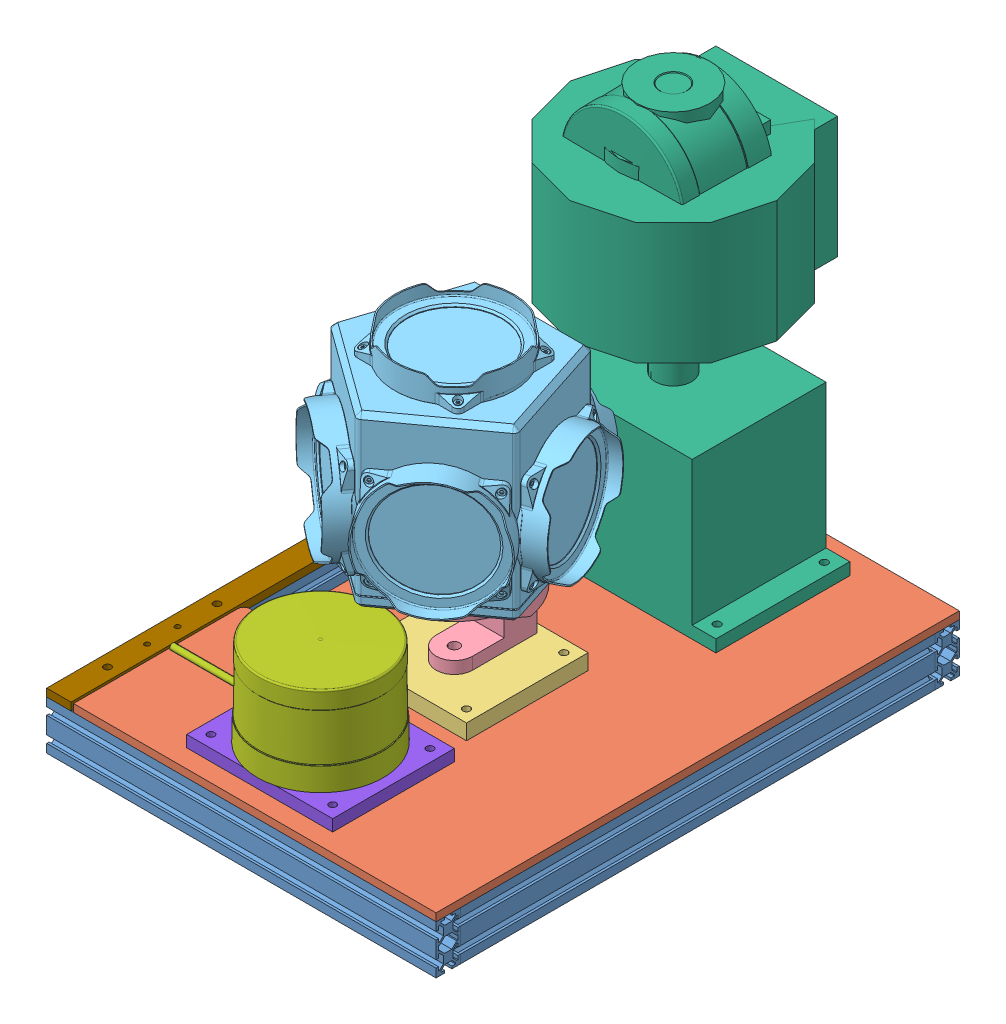
SolidWorks assembly complete_assembly, configuration Default. Lengths in mm.
Overall size (320 379.99 453.62).
14 component instances, 9 part files, 14 mates.
Components (placement in the parent):
- fence-1: fence [Default] at (0 -20 0) size (320 40 430)
  - 2040_extrusion-1: 2040_extrusion [320] at (0 20 205) x (0 0 1) z (-1 0 0) size (20 40 320)
  - 2040_extrusion-2: 2040_extrusion [390] at (150 20 0) size (20 40 390)
  - 2040_extrusion-3: 2040_extrusion [390] at (-150 20 0) x (-1 0 0) z (0 0 -1) size (20 40 390)
  - 2040_extrusion-4: 2040_extrusion [320] at (0 20 -205) x (0 0 -1) z (1 0 0) size (20 40 320)
- sensor_suite-1: sensor_suite [Default] at (0 20 0) size (298 339.99 453.62)
  - deck_lid-1: deck_lid [Default] at origin size (298 6.35 430)
  - Ladybug_mount_plate-1: Ladybug_mount_plate [Default] at (0 6.35 40) size (100 12.7 100)
  - OEM_Mount-1: OEM_Mount [Default] at (0 19.05 40) size (110 76.2 102.63)
  - LD5-001-R0-1: LD5-001-R0 [Default] at (0 155.75 40) x (-1 0 0) z (0 0 -1) size (192.91 159.78 183.75)
  - lidar_rotater-1: lidar_rotater [Default] at (0 6.35 -140) x (0 0 -1) z (1 0 0) size (197.23 333.64 197.23)
  - VLP-16-1: VLP-16 [Default] at (0 15.875 150) x (-1 0 0) z (0 0 -1) size (232.88 72.75 103.27)
  - Lidar_mount_plate-1: Lidar_mount_plate [Default] at (0 15.875 150) x (1 0 0) z (0 0 -1) size (120 9.53 100)
- Hinge_mount_plate-1: Hinge_mount_plate [Default] at (-150 20 0) x (-1 0 0) z (0 0 -1) size (20 6.35 430)
Mates (geometry in assembly coordinates):
- Coincident1: coincident aligned: plane of Fence-1 through (0 -20 0) normal (0 0 1); plane of assembly through (0 0 0) normal (0 0 1)
- Distance1: distance = 20 mm: plane of assembly through (0 0 0) normal (0 1 0); plane of Fence-1 through (0 -20 0) normal (0 1 0)
- Coincident3: coincident aligned: plane of Fence-1 through (0 -20 0) normal (1 0 0); plane of assembly through (0 0 0) normal (1 0 0)
- Coincident4: coincident aligned: plane of Plate_Sensors-1 through (0 20 0) normal (0 0 1); plane of assembly through (0 0 0) normal (0 0 1)
- Coincident5: coincident anti-aligned: plane of Fence-1/2040_extrusion-2 through (147 20 -195) normal (0 1 0); plane of Plate_Sensors-1/deck_lid-1 through (0 20 0) normal (0 -1 0)
- Coincident6: coincident aligned: plane of Plate_Sensors-1 through (0 20 0) normal (1 0 0); plane of assembly through (0 0 0) normal (1 0 0)
- Width1: width: plane of fence-1/2040_extrusion-3 through (-153 20 195) normal (1 0 0); plane of fence-1/2040_extrusion-3 through (-147 18 195) normal (-1 0 0); plane of ? through (-152.9 25.15 -112.5) normal (-1 0 0); plane of ? through (-147.1 24.35 -112.5) normal (1 0 0)
- Coincident7: coincident: plane of ? through (-139.5 26.35 -130) normal (0 -1 0); plane of sensor_suite-1/deck_lid-1 through (0 26.35 0) normal (0 1 0)
- Parallel1: parallel anti-aligned: line of fence-1/2040_extrusion-3 through (-153 20 195) axis (0 0 -1); line of ? through (-157.5 26.35 -153.5) axis (0 0 1)
- Concentric1: concentric: cylinder of ? through (-150 29.85 -117.5) axis (0 -1 0) radius 2.75; cylinder of Hinge_mount_plate-1 through (-150 26.35 -117.5) axis (0 1 0) radius 2.1
- Coincident11: coincident: plane of ? through (-139.5 26.35 -130) normal (0 -1 0); plane of Hinge_mount_plate-1 through (-150 26.35 0) normal (0 1 0)
- Coincident8: coincident anti-aligned: plane of Fence-1/2040_extrusion-3 through (-147 20 195) normal (0 1 0); plane of Hinge_mount_plate-1 through (-150 20 0) normal (0 -1 0)
- Coincident9: coincident anti-aligned: plane of Hinge_mount_plate-1 through (-150 20 0) normal (0 0 -1); plane of assembly through (0 0 0) normal (0 0 1)
- Coincident10: coincident aligned: plane of Fence-1/2040_extrusion-3 through (-150 0 0) normal (-1 0 0); plane of Hinge_mount_plate-1 through (-150 20 0) normal (-1 0 0)
